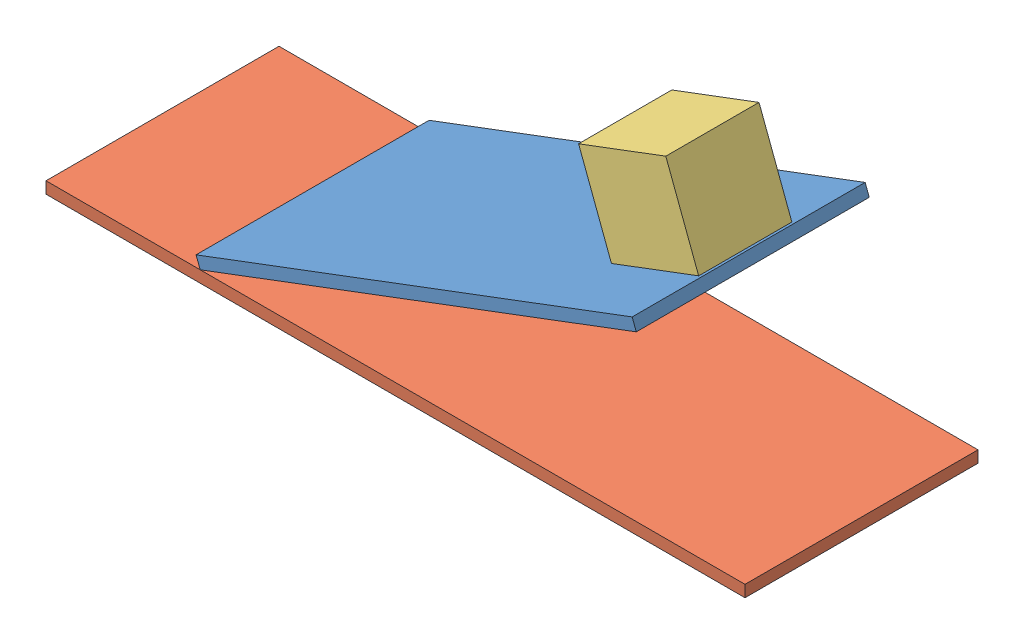
SolidWorks assembly Assemblage1, configuration Défaut. Lengths in mm.
Overall size (3000 1170.12 1000).
3 component instances, 3 part files, 5 mates.
Components (placement in the parent):
- planIncline-1: planIncline [Défaut] at (-721.2134 -495.3595 2016.0452) x (0.935815 0.352493 0) z (0 0 1) size (2000 50 1000)
- sol-1: sol [Défaut] at (-1382.9146 -545.3595 2016.0452) size (3000 50 1000)
- caisse-1: caisse [Défaut] at (742.5789 109.4355 2314.762) x (0.935815 0.352493 0) z (0 0 1) size (400 400 400)
Mates (geometry in assembly coordinates):
- Coïncidente1: coincident: line of planIncline-1 through (-721.2134 -495.3595 3016.0452) axis (0 0 -1); plane of sol-1 through (-1382.9146 -495.3595 3016.0452) normal (0 1 0)
- Coïncidente2: coincident aligned: plane of planIncline-1 through (-721.2134 -495.3595 3016.0452) normal (0 0 1); plane of sol-1 through (-1382.9146 -545.3595 3016.0452) normal (0 0 1)
- Coïncidente3: coincident: point of planIncline-1; point of sol-1
- Coïncidente4: coincident anti-aligned: plane of planIncline-1 through (-738.838 -448.5688 3016.0452) normal (-0.352493 0.935815 0); plane of caisse-1 through (742.5789 109.4355 2714.762) normal (0.352493 -0.935815 0)
- Coïncidente5: coincident anti-aligned: plane of planIncline-1; plane of sol-1 through (-1382.9146 -495.3595 3016.0452) normal (0 1 0)
